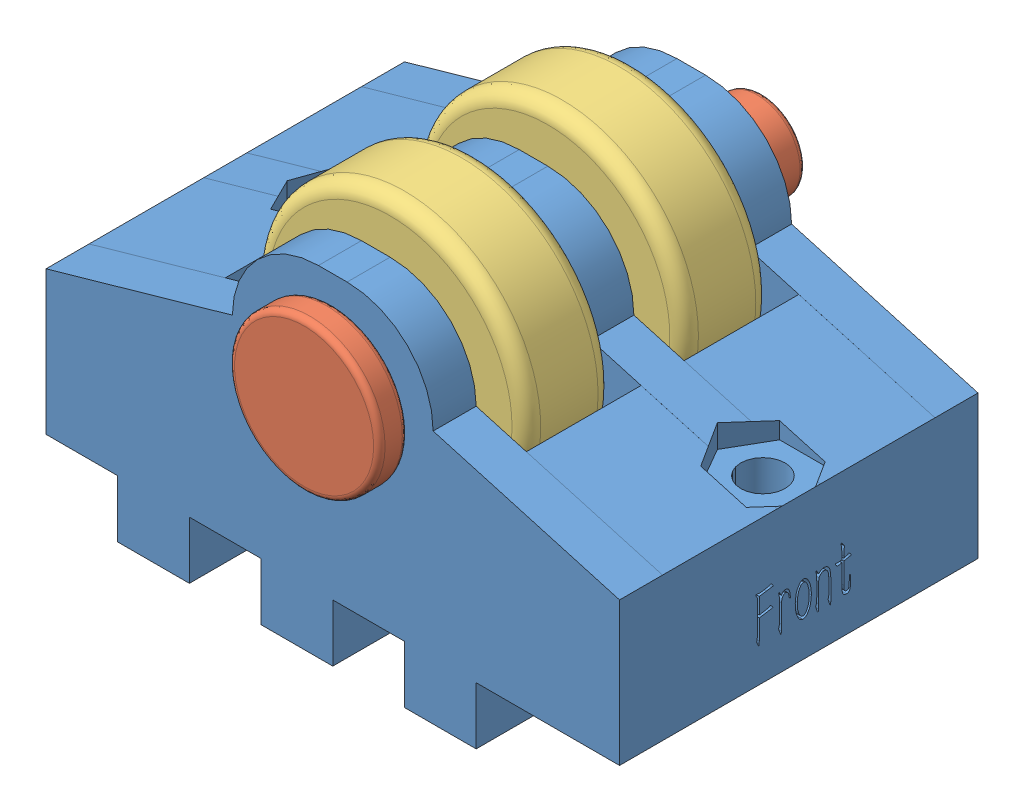
SolidWorks assembly 下定心组装体, configuration 默认. Lengths in mm.
Overall size (40 26.2 32).
4 component instances, 3 part files, 3 mates.
Components (placement in the parent):
- 下定心单打印件-1: 下定心单打印件 [默认] at (-136.6701 16.5899 12.5) size (40 23.7 25)
- 有效27直径6带槽圆柱销-1: 有效27直径6带槽圆柱销 [默认] at (-136.6701 9.5899 12.5) x (0 0 1) z (-1 0 0) size (32 10.5 10.5)
- 直径6厚度6外径19大轴承-1: 直径6厚度6外径19大轴承 [默认] at (-136.6701 9.5899 2.5) x (0 0 1) z (-1 0 0) size (6 19 19)
- 直径6厚度6外径19大轴承-2: 直径6厚度6外径19大轴承 [默认] at (-136.6701 9.5899 -8.5) x (0 0 1) z (-1 0 0) size (6 19 19)
Mates (geometry in assembly coordinates):
- 重合1: coincident anti-aligned: circle of 下定心打印件-1; circle of 直径6厚度6外径19大轴承-2
- 重合2: coincident anti-aligned: circle of 下定心打印件-1; circle of 直径6厚度6外径19大轴承-1
- 重合3: coincident anti-aligned: circle of 下定心打印件-1; circle of 有效27直径6带槽圆柱销-1
